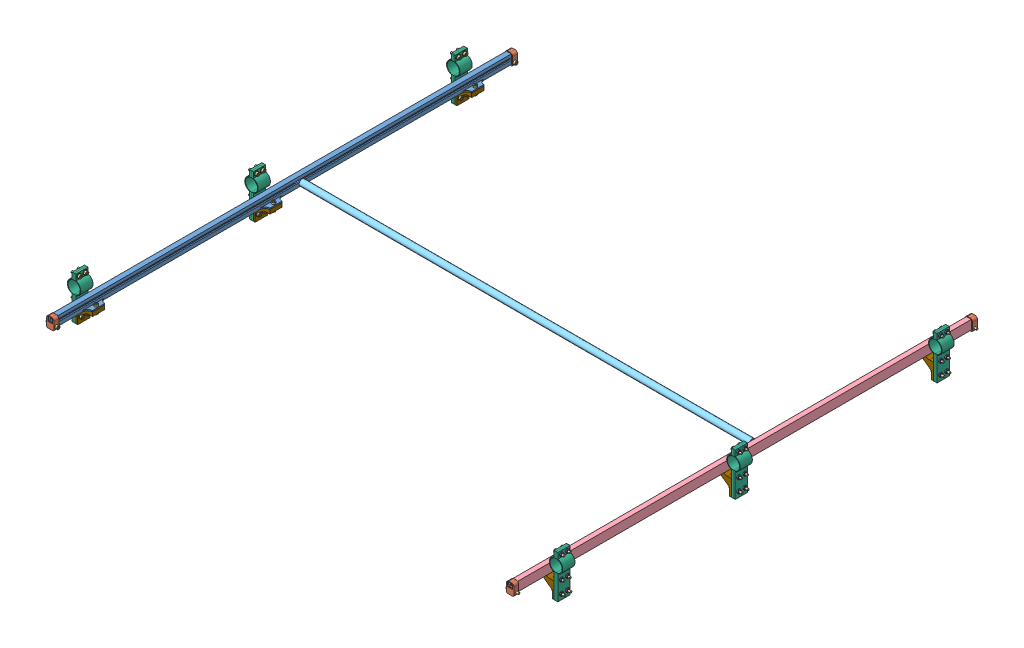
SolidWorks assembly 导轨, configuration 默认. Lengths in mm.
Overall size (810 70 758).
161 component instances, 9 part files, 34 mates.
Components (placement in the parent):
- 滑轨-1: 滑轨 [默认] at (7.799 -15.8903 -377.5) size (16 15 755)
- 滑轨孔套-1: 滑轨孔套 [默认] at (16.0944 -13.6499 379) x (-1 0 0) z (0 0 -1) size (12 18 8)
- 滑轨孔套-2: 滑轨孔套 [默认] at (8.0944 -13.6499 -379) size (12 18 8)
- hexagon socket head cap screws gb-2: hexagon socket head cap screws gb [GB_FASTENER_SCREWS_HSHCS M3X16-N] at (21.0944 -11.1499 374.5) x (-1 0 0) z (0 0.924225 0.381849) size (19 5.5 5.5)
- hexagon socket head cap screws gb-3: hexagon socket head cap screws gb [GB_FASTENER_SCREWS_HSHCS M3X16-N] at (21.0944 -11.1499 -374.5) x (-1 0 0) z (0 0.924225 0.381849) size (19 5.5 5.5)
- 滑轨-右-1: 滑轨-右 [默认] at (759.799 -15.8903 -377.5) size (16 15 755)
- hexagon socket head cap screws gb-4: hexagon socket head cap screws gb [GB_FASTENER_SCREWS_HSHCS M3X16-N] at (755.0944 -11.1499 -374.5) x (1 0 0) z (0 -0.924225 -0.381849) size (19 5.5 5.5)
- hexagon socket head cap screws gb-5: hexagon socket head cap screws gb [GB_FASTENER_SCREWS_HSHCS M3X16-N] at (755.0944 -11.1499 374.5) x (1 0 0) z (0 -0.924225 -0.381849) size (19 5.5 5.5)
- 滑轨孔套-3: 滑轨孔套 [默认] at (768.0944 -13.6499 379) x (-1 0 0) z (0 0 -1) size (12 18 8)
- 滑轨孔套-4: 滑轨孔套 [默认] at (760.0944 -13.6499 -379) size (12 18 8)
- 牵引杆-1: 牵引杆 [默认] at (8.0944 1.3501 -22.4841) x (1 0 0) z (0 0 -1) size (756 10.5 10)
- 导轨夹具-1: 导轨夹具 [默认] at (825.1435 -3.5468 -308) x (-1 0 0) z (0 0 -1) size (41 70 20)
  - 小管夹具-1: 小管夹具 [默认] at (-12.5658 -21.1975 0) size (22 70 20)
    - 夹具-1: 夹具 [默认] at (55.615 31.0944 -10) size (11 70 20)
    - 夹具-2: 夹具 [默认] at (55.615 31.0944 10) x (-1 0 0) z (0 0 -1) size (11 70 20)
    - plain washers-n series-grade a gb-2: plain washers-n series-grade a gb [GB_FASTENER_WASHER_PWNA 3] at (59.115 46.3859 5) x (0 0 -1) z (1 0 0) size (7 7 0.5)
    - plain washers-n series-grade a gb-3: plain washers-n series-grade a gb [GB_FASTENER_WASHER_PWNA 3] at (59.115 46.3859 -5) x (0 0 -1) z (1 0 0) size (7 7 0.5)
    - plain washers-n series-grade a gb-4: plain washers-n series-grade a gb [GB_FASTENER_WASHER_PWNA 3] at (59.115 10.8029 -5) x (0 0 -1) z (1 0 0) size (7 7 0.5)
    - plain washers-n series-grade a gb-5: plain washers-n series-grade a gb [GB_FASTENER_WASHER_PWNA 3] at (59.115 10.8029 5) x (0 0 -1) z (1 0 0) size (7 7 0.5)
    - hexagon socket head cap screws gb-2: hexagon socket head cap screws gb [GB_FASTENER_SCREWS_HSHCS M3X12-N] at (62.115 10.8029 -5) x (-1 0 0) z (0 0.924225 0.381849) size (15 5.5 5.5)
    - hexagon socket head cap screws gb-3: hexagon socket head cap screws gb [GB_FASTENER_SCREWS_HSHCS M3X12-N] at (62.115 10.8029 5) x (-1 0 0) z (0 0.924225 0.381849) size (15 5.5 5.5)
    - hexagon socket head cap screws gb-4: hexagon socket head cap screws gb [GB_FASTENER_SCREWS_HSHCS M3X12-N] at (62.115 46.3859 -5) x (-1 0 0) z (0 0.924225 0.381849) size (15 5.5 5.5)
    - hexagon socket head cap screws gb-5: hexagon socket head cap screws gb [GB_FASTENER_SCREWS_HSHCS M3X12-N] at (62.115 46.3859 5) x (-1 0 0) z (0 0.924225 0.381849) size (15 5.5 5.5)
    - hex nuts, style 1-grades ab gb-2: hex nuts, style 1-grades ab gb [GB_FASTENER_NUT_SNAB1 M3-N] at (50.215 10.8029 -5) x (0 0 1) z (-1 0 0) size (6.35 5.5 2.4)
    - hex nuts, style 1-grades ab gb-3: hex nuts, style 1-grades ab gb [GB_FASTENER_NUT_SNAB1 M3-N] at (50.215 10.8029 5) x (0 0 1) z (-1 0 0) size (6.35 5.5 2.4)
    - hex nuts, style 1-grades ab gb-4: hex nuts, style 1-grades ab gb [GB_FASTENER_NUT_SNAB1 M3-N] at (50.215 46.3859 -5) x (0 0 1) z (-1 0 0) size (6.35 5.5 2.4)
    - hex nuts, style 1-grades ab gb-5: hex nuts, style 1-grades ab gb [GB_FASTENER_NUT_SNAB1 M3-N] at (50.215 46.3859 5) x (0 0 1) z (-1 0 0) size (6.35 5.5 2.4)
  - 滑轨支架-1: 滑轨支架 [默认] at (49.0492 14.8969 -10) x (0 0 1) z (-1 0 0) size (20 30 27)
  - plain washers-n series-grade a gb-2: plain washers-n series-grade a gb [GB_FASTENER_WASHER_PWNA 3] at (49.5492 -30.3946 5) x (0 0 -1) z (1 0 0) size (7 7 0.5)
  - plain washers-n series-grade a gb-3: plain washers-n series-grade a gb [GB_FASTENER_WASHER_PWNA 3] at (49.5492 -30.3946 -5) x (0 0 -1) z (1 0 0) size (7 7 0.5)
  - hexagon socket head cap screws gb-2: hexagon socket head cap screws gb [GB_FASTENER_SCREWS_HSHCS M3X16-N] at (52.5492 -30.3946 5) x (-1 0 0) z (0 0.924225 0.381849) size (19 5.5 5.5)
  - hexagon socket head cap screws gb-3: hexagon socket head cap screws gb [GB_FASTENER_SCREWS_HSHCS M3X16-N] at (52.5492 -30.3946 -5) x (-1 0 0) z (0 0.924225 0.381849) size (19 5.5 5.5)
  - hex nuts, style 1-grades ab gb-2: hex nuts, style 1-grades ab gb [GB_FASTENER_NUT_SNAB1 M3-N] at (37.6492 -30.3946 5) x (0 0 1) z (-1 0 0) size (6.35 5.5 2.4)
  - hex nuts, style 1-grades ab gb-3: hex nuts, style 1-grades ab gb [GB_FASTENER_NUT_SNAB1 M3-N] at (37.6492 -30.3946 -5) x (0 0 1) z (-1 0 0) size (6.35 5.5 2.4)
- 导轨夹具-2: 导轨夹具 [默认] at (825.1435 -3.5468 22) x (-1 0 0) z (0 0 -1) size (41 70 20)
  - 小管夹具-1: 小管夹具 [默认] at (-12.5658 -21.1975 0) size (22 70 20)
    - 夹具-1: 夹具 [默认] at (55.615 31.0944 -10) size (11 70 20)
    - 夹具-2: 夹具 [默认] at (55.615 31.0944 10) x (-1 0 0) z (0 0 -1) size (11 70 20)
    - plain washers-n series-grade a gb-2: plain washers-n series-grade a gb [GB_FASTENER_WASHER_PWNA 3] at (59.115 46.3859 5) x (0 0 -1) z (1 0 0) size (7 7 0.5)
    - plain washers-n series-grade a gb-3: plain washers-n series-grade a gb [GB_FASTENER_WASHER_PWNA 3] at (59.115 46.3859 -5) x (0 0 -1) z (1 0 0) size (7 7 0.5)
    - plain washers-n series-grade a gb-4: plain washers-n series-grade a gb [GB_FASTENER_WASHER_PWNA 3] at (59.115 10.8029 -5) x (0 0 -1) z (1 0 0) size (7 7 0.5)
    - plain washers-n series-grade a gb-5: plain washers-n series-grade a gb [GB_FASTENER_WASHER_PWNA 3] at (59.115 10.8029 5) x (0 0 -1) z (1 0 0) size (7 7 0.5)
    - hexagon socket head cap screws gb-2: hexagon socket head cap screws gb [GB_FASTENER_SCREWS_HSHCS M3X12-N] at (62.115 10.8029 -5) x (-1 0 0) z (0 0.924225 0.381849) size (15 5.5 5.5)
    - hexagon socket head cap screws gb-3: hexagon socket head cap screws gb [GB_FASTENER_SCREWS_HSHCS M3X12-N] at (62.115 10.8029 5) x (-1 0 0) z (0 0.924225 0.381849) size (15 5.5 5.5)
    - hexagon socket head cap screws gb-4: hexagon socket head cap screws gb [GB_FASTENER_SCREWS_HSHCS M3X12-N] at (62.115 46.3859 -5) x (-1 0 0) z (0 0.924225 0.381849) size (15 5.5 5.5)
    - hexagon socket head cap screws gb-5: hexagon socket head cap screws gb [GB_FASTENER_SCREWS_HSHCS M3X12-N] at (62.115 46.3859 5) x (-1 0 0) z (0 0.924225 0.381849) size (15 5.5 5.5)
    - hex nuts, style 1-grades ab gb-2: hex nuts, style 1-grades ab gb [GB_FASTENER_NUT_SNAB1 M3-N] at (50.215 10.8029 -5) x (0 0 1) z (-1 0 0) size (6.35 5.5 2.4)
    - hex nuts, style 1-grades ab gb-3: hex nuts, style 1-grades ab gb [GB_FASTENER_NUT_SNAB1 M3-N] at (50.215 10.8029 5) x (0 0 1) z (-1 0 0) size (6.35 5.5 2.4)
    - hex nuts, style 1-grades ab gb-4: hex nuts, style 1-grades ab gb [GB_FASTENER_NUT_SNAB1 M3-N] at (50.215 46.3859 -5) x (0 0 1) z (-1 0 0) size (6.35 5.5 2.4)
    - hex nuts, style 1-grades ab gb-5: hex nuts, style 1-grades ab gb [GB_FASTENER_NUT_SNAB1 M3-N] at (50.215 46.3859 5) x (0 0 1) z (-1 0 0) size (6.35 5.5 2.4)
  - 滑轨支架-1: 滑轨支架 [默认] at (49.0492 14.8969 -10) x (0 0 1) z (-1 0 0) size (20 30 27)
  - plain washers-n series-grade a gb-2: plain washers-n series-grade a gb [GB_FASTENER_WASHER_PWNA 3] at (49.5492 -30.3946 5) x (0 0 -1) z (1 0 0) size (7 7 0.5)
  - plain washers-n series-grade a gb-3: plain washers-n series-grade a gb [GB_FASTENER_WASHER_PWNA 3] at (49.5492 -30.3946 -5) x (0 0 -1) z (1 0 0) size (7 7 0.5)
  - hexagon socket head cap screws gb-2: hexagon socket head cap screws gb [GB_FASTENER_SCREWS_HSHCS M3X16-N] at (52.5492 -30.3946 5) x (-1 0 0) z (0 0.924225 0.381849) size (19 5.5 5.5)
  - hexagon socket head cap screws gb-3: hexagon socket head cap screws gb [GB_FASTENER_SCREWS_HSHCS M3X16-N] at (52.5492 -30.3946 -5) x (-1 0 0) z (0 0.924225 0.381849) size (19 5.5 5.5)
  - hex nuts, style 1-grades ab gb-2: hex nuts, style 1-grades ab gb [GB_FASTENER_NUT_SNAB1 M3-N] at (37.6492 -30.3946 5) x (0 0 1) z (-1 0 0) size (6.35 5.5 2.4)
  - hex nuts, style 1-grades ab gb-3: hex nuts, style 1-grades ab gb [GB_FASTENER_NUT_SNAB1 M3-N] at (37.6492 -30.3946 -5) x (0 0 1) z (-1 0 0) size (6.35 5.5 2.4)
- 导轨夹具-3: 导轨夹具 [默认] at (825.1435 -3.5468 312) x (-1 0 0) z (0 0 -1) size (41 70 20)
  - 小管夹具-1: 小管夹具 [默认] at (-12.5658 -21.1975 0) size (22 70 20)
    - 夹具-1: 夹具 [默认] at (55.615 31.0944 -10) size (11 70 20)
    - 夹具-2: 夹具 [默认] at (55.615 31.0944 10) x (-1 0 0) z (0 0 -1) size (11 70 20)
    - plain washers-n series-grade a gb-2: plain washers-n series-grade a gb [GB_FASTENER_WASHER_PWNA 3] at (59.115 46.3859 5) x (0 0 -1) z (1 0 0) size (7 7 0.5)
    - plain washers-n series-grade a gb-3: plain washers-n series-grade a gb [GB_FASTENER_WASHER_PWNA 3] at (59.115 46.3859 -5) x (0 0 -1) z (1 0 0) size (7 7 0.5)
    - plain washers-n series-grade a gb-4: plain washers-n series-grade a gb [GB_FASTENER_WASHER_PWNA 3] at (59.115 10.8029 -5) x (0 0 -1) z (1 0 0) size (7 7 0.5)
    - plain washers-n series-grade a gb-5: plain washers-n series-grade a gb [GB_FASTENER_WASHER_PWNA 3] at (59.115 10.8029 5) x (0 0 -1) z (1 0 0) size (7 7 0.5)
    - hexagon socket head cap screws gb-2: hexagon socket head cap screws gb [GB_FASTENER_SCREWS_HSHCS M3X12-N] at (62.115 10.8029 -5) x (-1 0 0) z (0 0.924225 0.381849) size (15 5.5 5.5)
    - hexagon socket head cap screws gb-3: hexagon socket head cap screws gb [GB_FASTENER_SCREWS_HSHCS M3X12-N] at (62.115 10.8029 5) x (-1 0 0) z (0 0.924225 0.381849) size (15 5.5 5.5)
    - hexagon socket head cap screws gb-4: hexagon socket head cap screws gb [GB_FASTENER_SCREWS_HSHCS M3X12-N] at (62.115 46.3859 -5) x (-1 0 0) z (0 0.924225 0.381849) size (15 5.5 5.5)
    - hexagon socket head cap screws gb-5: hexagon socket head cap screws gb [GB_FASTENER_SCREWS_HSHCS M3X12-N] at (62.115 46.3859 5) x (-1 0 0) z (0 0.924225 0.381849) size (15 5.5 5.5)
    - hex nuts, style 1-grades ab gb-2: hex nuts, style 1-grades ab gb [GB_FASTENER_NUT_SNAB1 M3-N] at (50.215 10.8029 -5) x (0 0 1) z (-1 0 0) size (6.35 5.5 2.4)
    - hex nuts, style 1-grades ab gb-3: hex nuts, style 1-grades ab gb [GB_FASTENER_NUT_SNAB1 M3-N] at (50.215 10.8029 5) x (0 0 1) z (-1 0 0) size (6.35 5.5 2.4)
    - hex nuts, style 1-grades ab gb-4: hex nuts, style 1-grades ab gb [GB_FASTENER_NUT_SNAB1 M3-N] at (50.215 46.3859 -5) x (0 0 1) z (-1 0 0) size (6.35 5.5 2.4)
    - hex nuts, style 1-grades ab gb-5: hex nuts, style 1-grades ab gb [GB_FASTENER_NUT_SNAB1 M3-N] at (50.215 46.3859 5) x (0 0 1) z (-1 0 0) size (6.35 5.5 2.4)
  - 滑轨支架-1: 滑轨支架 [默认] at (49.0492 14.8969 -10) x (0 0 1) z (-1 0 0) size (20 30 27)
  - plain washers-n series-grade a gb-2: plain washers-n series-grade a gb [GB_FASTENER_WASHER_PWNA 3] at (49.5492 -30.3946 5) x (0 0 -1) z (1 0 0) size (7 7 0.5)
  - plain washers-n series-grade a gb-3: plain washers-n series-grade a gb [GB_FASTENER_WASHER_PWNA 3] at (49.5492 -30.3946 -5) x (0 0 -1) z (1 0 0) size (7 7 0.5)
  - hexagon socket head cap screws gb-2: hexagon socket head cap screws gb [GB_FASTENER_SCREWS_HSHCS M3X16-N] at (52.5492 -30.3946 5) x (-1 0 0) z (0 0.924225 0.381849) size (19 5.5 5.5)
  - hexagon socket head cap screws gb-3: hexagon socket head cap screws gb [GB_FASTENER_SCREWS_HSHCS M3X16-N] at (52.5492 -30.3946 -5) x (-1 0 0) z (0 0.924225 0.381849) size (19 5.5 5.5)
  - hex nuts, style 1-grades ab gb-2: hex nuts, style 1-grades ab gb [GB_FASTENER_NUT_SNAB1 M3-N] at (37.6492 -30.3946 5) x (0 0 1) z (-1 0 0) size (6.35 5.5 2.4)
  - hex nuts, style 1-grades ab gb-3: hex nuts, style 1-grades ab gb [GB_FASTENER_NUT_SNAB1 M3-N] at (37.6492 -30.3946 -5) x (0 0 1) z (-1 0 0) size (6.35 5.5 2.4)
- hexagon socket head cap screws gb-9: hexagon socket head cap screws gb [GB_FASTENER_SCREWS_HSHCS M3X12-N] at (756.0944 -8.6499 312) x (0 -1 0) z (0 0 1) size (15 5.5 5.5)
- hexagon socket head cap screws gb-10: hexagon socket head cap screws gb [GB_FASTENER_SCREWS_HSHCS M3X12-N] at (756.0944 -8.6499 22) x (0 -1 0) z (0 0 1) size (15 5.5 5.5)
- hexagon socket head cap screws gb-11: hexagon socket head cap screws gb [GB_FASTENER_SCREWS_HSHCS M3X12-N] at (756.0944 -8.6499 -308) x (0 -1 0) z (0 0 1) size (15 5.5 5.5)
- hex nuts, style 1-grades ab gb-2: hex nuts, style 1-grades ab gb [GB_FASTENER_NUT_SNAB1 M3-N] at (756.0944 -22.5499 22) x (1 0 0) z (0 -1 0) size (6.35 5.5 2.4)
- hex nuts, style 1-grades ab gb-4: hex nuts, style 1-grades ab gb [GB_FASTENER_NUT_SNAB1 M3-N] at (756.0944 -22.5499 -308) x (1 0 0) z (0 -1 0) size (6.35 5.5 2.4)
- hex nuts, style 1-grades ab gb-5: hex nuts, style 1-grades ab gb [GB_FASTENER_NUT_SNAB1 M3-N] at (756.0944 -22.5499 312) x (1 0 0) z (0 -1 0) size (6.35 5.5 2.4)
- hex nuts, style 1-grades ab gb-9: hex nuts, style 1-grades ab gb [GB_FASTENER_NUT_SNAB1 M3-N] at (20.0944 -20.1499 312) x (-1 0 0) z (0 1 0) size (6.35 5.5 2.4)
- hex nuts, style 1-grades ab gb-10: hex nuts, style 1-grades ab gb [GB_FASTENER_NUT_SNAB1 M3-N] at (20.0944 -20.1499 -308) x (-1 0 0) z (0 1 0) size (6.35 5.5 2.4)
- hex nuts, style 1-grades ab gb-11: hex nuts, style 1-grades ab gb [GB_FASTENER_NUT_SNAB1 M3-N] at (20.0944 -20.1499 22) x (-1 0 0) z (0 1 0) size (6.35 5.5 2.4)
- hexagon socket head cap screws gb-15: hexagon socket head cap screws gb [GB_FASTENER_SCREWS_HSHCS M3X12-N] at (20.0944 -8.6499 -308) x (0 -1 0) z (0 0 -1) size (15 5.5 5.5)
- hexagon socket head cap screws gb-16: hexagon socket head cap screws gb [GB_FASTENER_SCREWS_HSHCS M3X12-N] at (20.0944 -8.6499 22) x (0 -1 0) z (0 0 -1) size (15 5.5 5.5)
- hexagon socket head cap screws gb-17: hexagon socket head cap screws gb [GB_FASTENER_SCREWS_HSHCS M3X12-N] at (20.0944 -8.6499 312) x (0 -1 0) z (0 0 -1) size (15 5.5 5.5)
- 导轨夹具-5: 导轨夹具 [默认] at (-48.9548 -3.5468 312) size (41 70 20)
  - 小管夹具-1: 小管夹具 [默认] at (-12.5658 -21.1975 0) size (22 70 20)
    - 夹具-1: 夹具 [默认] at (55.615 31.0944 -10) size (11 70 20)
    - 夹具-2: 夹具 [默认] at (55.615 31.0944 10) x (-1 0 0) z (0 0 -1) size (11 70 20)
    - plain washers-n series-grade a gb-2: plain washers-n series-grade a gb [GB_FASTENER_WASHER_PWNA 3] at (59.115 46.3859 5) x (0 0 -1) z (1 0 0) size (7 7 0.5)
    - plain washers-n series-grade a gb-3: plain washers-n series-grade a gb [GB_FASTENER_WASHER_PWNA 3] at (59.115 46.3859 -5) x (0 0 -1) z (1 0 0) size (7 7 0.5)
    - plain washers-n series-grade a gb-4: plain washers-n series-grade a gb [GB_FASTENER_WASHER_PWNA 3] at (59.115 10.8029 -5) x (0 0 -1) z (1 0 0) size (7 7 0.5)
    - plain washers-n series-grade a gb-5: plain washers-n series-grade a gb [GB_FASTENER_WASHER_PWNA 3] at (59.115 10.8029 5) x (0 0 -1) z (1 0 0) size (7 7 0.5)
    - hexagon socket head cap screws gb-2: hexagon socket head cap screws gb [GB_FASTENER_SCREWS_HSHCS M3X12-N] at (62.115 10.8029 -5) x (-1 0 0) z (0 0.924225 0.381849) size (15 5.5 5.5)
    - hexagon socket head cap screws gb-3: hexagon socket head cap screws gb [GB_FASTENER_SCREWS_HSHCS M3X12-N] at (62.115 10.8029 5) x (-1 0 0) z (0 0.924225 0.381849) size (15 5.5 5.5)
    - hexagon socket head cap screws gb-4: hexagon socket head cap screws gb [GB_FASTENER_SCREWS_HSHCS M3X12-N] at (62.115 46.3859 -5) x (-1 0 0) z (0 0.924225 0.381849) size (15 5.5 5.5)
    - hexagon socket head cap screws gb-5: hexagon socket head cap screws gb [GB_FASTENER_SCREWS_HSHCS M3X12-N] at (62.115 46.3859 5) x (-1 0 0) z (0 0.924225 0.381849) size (15 5.5 5.5)
    - hex nuts, style 1-grades ab gb-2: hex nuts, style 1-grades ab gb [GB_FASTENER_NUT_SNAB1 M3-N] at (50.215 10.8029 -5) x (0 0 1) z (-1 0 0) size (6.35 5.5 2.4)
    - hex nuts, style 1-grades ab gb-3: hex nuts, style 1-grades ab gb [GB_FASTENER_NUT_SNAB1 M3-N] at (50.215 10.8029 5) x (0 0 1) z (-1 0 0) size (6.35 5.5 2.4)
    - hex nuts, style 1-grades ab gb-4: hex nuts, style 1-grades ab gb [GB_FASTENER_NUT_SNAB1 M3-N] at (50.215 46.3859 -5) x (0 0 1) z (-1 0 0) size (6.35 5.5 2.4)
    - hex nuts, style 1-grades ab gb-5: hex nuts, style 1-grades ab gb [GB_FASTENER_NUT_SNAB1 M3-N] at (50.215 46.3859 5) x (0 0 1) z (-1 0 0) size (6.35 5.5 2.4)
  - 滑轨支架-1: 滑轨支架 [默认] at (49.0492 14.8969 -10) x (0 0 1) z (-1 0 0) size (20 30 27)
  - plain washers-n series-grade a gb-2: plain washers-n series-grade a gb [GB_FASTENER_WASHER_PWNA 3] at (49.5492 -30.3946 5) x (0 0 -1) z (1 0 0) size (7 7 0.5)
  - plain washers-n series-grade a gb-3: plain washers-n series-grade a gb [GB_FASTENER_WASHER_PWNA 3] at (49.5492 -30.3946 -5) x (0 0 -1) z (1 0 0) size (7 7 0.5)
  - hexagon socket head cap screws gb-2: hexagon socket head cap screws gb [GB_FASTENER_SCREWS_HSHCS M3X16-N] at (52.5492 -30.3946 5) x (-1 0 0) z (0 0.924225 0.381849) size (19 5.5 5.5)
  - hexagon socket head cap screws gb-3: hexagon socket head cap screws gb [GB_FASTENER_SCREWS_HSHCS M3X16-N] at (52.5492 -30.3946 -5) x (-1 0 0) z (0 0.924225 0.381849) size (19 5.5 5.5)
  - hex nuts, style 1-grades ab gb-2: hex nuts, style 1-grades ab gb [GB_FASTENER_NUT_SNAB1 M3-N] at (37.6492 -30.3946 5) x (0 0 1) z (-1 0 0) size (6.35 5.5 2.4)
  - hex nuts, style 1-grades ab gb-3: hex nuts, style 1-grades ab gb [GB_FASTENER_NUT_SNAB1 M3-N] at (37.6492 -30.3946 -5) x (0 0 1) z (-1 0 0) size (6.35 5.5 2.4)
- 导轨夹具-6: 导轨夹具 [默认] at (-48.9548 -3.5468 -308) size (41 70 20)
  - 小管夹具-1: 小管夹具 [默认] at (-12.5658 -21.1975 0) size (22 70 20)
    - 夹具-1: 夹具 [默认] at (55.615 31.0944 -10) size (11 70 20)
    - 夹具-2: 夹具 [默认] at (55.615 31.0944 10) x (-1 0 0) z (0 0 -1) size (11 70 20)
    - plain washers-n series-grade a gb-2: plain washers-n series-grade a gb [GB_FASTENER_WASHER_PWNA 3] at (59.115 46.3859 5) x (0 0 -1) z (1 0 0) size (7 7 0.5)
    - plain washers-n series-grade a gb-3: plain washers-n series-grade a gb [GB_FASTENER_WASHER_PWNA 3] at (59.115 46.3859 -5) x (0 0 -1) z (1 0 0) size (7 7 0.5)
    - plain washers-n series-grade a gb-4: plain washers-n series-grade a gb [GB_FASTENER_WASHER_PWNA 3] at (59.115 10.8029 -5) x (0 0 -1) z (1 0 0) size (7 7 0.5)
    - plain washers-n series-grade a gb-5: plain washers-n series-grade a gb [GB_FASTENER_WASHER_PWNA 3] at (59.115 10.8029 5) x (0 0 -1) z (1 0 0) size (7 7 0.5)
    - hexagon socket head cap screws gb-2: hexagon socket head cap screws gb [GB_FASTENER_SCREWS_HSHCS M3X12-N] at (62.115 10.8029 -5) x (-1 0 0) z (0 0.924225 0.381849) size (15 5.5 5.5)
    - hexagon socket head cap screws gb-3: hexagon socket head cap screws gb [GB_FASTENER_SCREWS_HSHCS M3X12-N] at (62.115 10.8029 5) x (-1 0 0) z (0 0.924225 0.381849) size (15 5.5 5.5)
    - hexagon socket head cap screws gb-4: hexagon socket head cap screws gb [GB_FASTENER_SCREWS_HSHCS M3X12-N] at (62.115 46.3859 -5) x (-1 0 0) z (0 0.924225 0.381849) size (15 5.5 5.5)
    - hexagon socket head cap screws gb-5: hexagon socket head cap screws gb [GB_FASTENER_SCREWS_HSHCS M3X12-N] at (62.115 46.3859 5) x (-1 0 0) z (0 0.924225 0.381849) size (15 5.5 5.5)
    - hex nuts, style 1-grades ab gb-2: hex nuts, style 1-grades ab gb [GB_FASTENER_NUT_SNAB1 M3-N] at (50.215 10.8029 -5) x (0 0 1) z (-1 0 0) size (6.35 5.5 2.4)
    - hex nuts, style 1-grades ab gb-3: hex nuts, style 1-grades ab gb [GB_FASTENER_NUT_SNAB1 M3-N] at (50.215 10.8029 5) x (0 0 1) z (-1 0 0) size (6.35 5.5 2.4)
    - hex nuts, style 1-grades ab gb-4: hex nuts, style 1-grades ab gb [GB_FASTENER_NUT_SNAB1 M3-N] at (50.215 46.3859 -5) x (0 0 1) z (-1 0 0) size (6.35 5.5 2.4)
    - hex nuts, style 1-grades ab gb-5: hex nuts, style 1-grades ab gb [GB_FASTENER_NUT_SNAB1 M3-N] at (50.215 46.3859 5) x (0 0 1) z (-1 0 0) size (6.35 5.5 2.4)
  - 滑轨支架-1: 滑轨支架 [默认] at (49.0492 14.8969 -10) x (0 0 1) z (-1 0 0) size (20 30 27)
  - plain washers-n series-grade a gb-2: plain washers-n series-grade a gb [GB_FASTENER_WASHER_PWNA 3] at (49.5492 -30.3946 5) x (0 0 -1) z (1 0 0) size (7 7 0.5)
  - plain washers-n series-grade a gb-3: plain washers-n series-grade a gb [GB_FASTENER_WASHER_PWNA 3] at (49.5492 -30.3946 -5) x (0 0 -1) z (1 0 0) size (7 7 0.5)
  - hexagon socket head cap screws gb-2: hexagon socket head cap screws gb [GB_FASTENER_SCREWS_HSHCS M3X16-N] at (52.5492 -30.3946 5) x (-1 0 0) z (0 0.924225 0.381849) size (19 5.5 5.5)
  - hexagon socket head cap screws gb-3: hexagon socket head cap screws gb [GB_FASTENER_SCREWS_HSHCS M3X16-N] at (52.5492 -30.3946 -5) x (-1 0 0) z (0 0.924225 0.381849) size (19 5.5 5.5)
  - hex nuts, style 1-grades ab gb-2: hex nuts, style 1-grades ab gb [GB_FASTENER_NUT_SNAB1 M3-N] at (37.6492 -30.3946 5) x (0 0 1) z (-1 0 0) size (6.35 5.5 2.4)
  - hex nuts, style 1-grades ab gb-3: hex nuts, style 1-grades ab gb [GB_FASTENER_NUT_SNAB1 M3-N] at (37.6492 -30.3946 -5) x (0 0 1) z (-1 0 0) size (6.35 5.5 2.4)
- 导轨夹具-7: 导轨夹具 [默认] at (-48.9548 -3.5468 22) size (41 70 20)
  - 小管夹具-1: 小管夹具 [默认] at (-12.5658 -21.1975 0) size (22 70 20)
    - 夹具-1: 夹具 [默认] at (55.615 31.0944 -10) size (11 70 20)
    - 夹具-2: 夹具 [默认] at (55.615 31.0944 10) x (-1 0 0) z (0 0 -1) size (11 70 20)
    - plain washers-n series-grade a gb-2: plain washers-n series-grade a gb [GB_FASTENER_WASHER_PWNA 3] at (59.115 46.3859 5) x (0 0 -1) z (1 0 0) size (7 7 0.5)
    - plain washers-n series-grade a gb-3: plain washers-n series-grade a gb [GB_FASTENER_WASHER_PWNA 3] at (59.115 46.3859 -5) x (0 0 -1) z (1 0 0) size (7 7 0.5)
    - plain washers-n series-grade a gb-4: plain washers-n series-grade a gb [GB_FASTENER_WASHER_PWNA 3] at (59.115 10.8029 -5) x (0 0 -1) z (1 0 0) size (7 7 0.5)
    - plain washers-n series-grade a gb-5: plain washers-n series-grade a gb [GB_FASTENER_WASHER_PWNA 3] at (59.115 10.8029 5) x (0 0 -1) z (1 0 0) size (7 7 0.5)
    - hexagon socket head cap screws gb-2: hexagon socket head cap screws gb [GB_FASTENER_SCREWS_HSHCS M3X12-N] at (62.115 10.8029 -5) x (-1 0 0) z (0 0.924225 0.381849) size (15 5.5 5.5)
    - hexagon socket head cap screws gb-3: hexagon socket head cap screws gb [GB_FASTENER_SCREWS_HSHCS M3X12-N] at (62.115 10.8029 5) x (-1 0 0) z (0 0.924225 0.381849) size (15 5.5 5.5)
    - hexagon socket head cap screws gb-4: hexagon socket head cap screws gb [GB_FASTENER_SCREWS_HSHCS M3X12-N] at (62.115 46.3859 -5) x (-1 0 0) z (0 0.924225 0.381849) size (15 5.5 5.5)
    - hexagon socket head cap screws gb-5: hexagon socket head cap screws gb [GB_FASTENER_SCREWS_HSHCS M3X12-N] at (62.115 46.3859 5) x (-1 0 0) z (0 0.924225 0.381849) size (15 5.5 5.5)
    - hex nuts, style 1-grades ab gb-2: hex nuts, style 1-grades ab gb [GB_FASTENER_NUT_SNAB1 M3-N] at (50.215 10.8029 -5) x (0 0 1) z (-1 0 0) size (6.35 5.5 2.4)
    - hex nuts, style 1-grades ab gb-3: hex nuts, style 1-grades ab gb [GB_FASTENER_NUT_SNAB1 M3-N] at (50.215 10.8029 5) x (0 0 1) z (-1 0 0) size (6.35 5.5 2.4)
    - hex nuts, style 1-grades ab gb-4: hex nuts, style 1-grades ab gb [GB_FASTENER_NUT_SNAB1 M3-N] at (50.215 46.3859 -5) x (0 0 1) z (-1 0 0) size (6.35 5.5 2.4)
    - hex nuts, style 1-grades ab gb-5: hex nuts, style 1-grades ab gb [GB_FASTENER_NUT_SNAB1 M3-N] at (50.215 46.3859 5) x (0 0 1) z (-1 0 0) size (6.35 5.5 2.4)
  - 滑轨支架-1: 滑轨支架 [默认] at (49.0492 14.8969 -10) x (0 0 1) z (-1 0 0) size (20 30 27)
  - plain washers-n series-grade a gb-2: plain washers-n series-grade a gb [GB_FASTENER_WASHER_PWNA 3] at (49.5492 -30.3946 5) x (0 0 -1) z (1 0 0) size (7 7 0.5)
  - plain washers-n series-grade a gb-3: plain washers-n series-grade a gb [GB_FASTENER_WASHER_PWNA 3] at (49.5492 -30.3946 -5) x (0 0 -1) z (1 0 0) size (7 7 0.5)
  - hexagon socket head cap screws gb-2: hexagon socket head cap screws gb [GB_FASTENER_SCREWS_HSHCS M3X16-N] at (52.5492 -30.3946 5) x (-1 0 0) z (0 0.924225 0.381849) size (19 5.5 5.5)
  - hexagon socket head cap screws gb-3: hexagon socket head cap screws gb [GB_FASTENER_SCREWS_HSHCS M3X16-N] at (52.5492 -30.3946 -5) x (-1 0 0) z (0 0.924225 0.381849) size (19 5.5 5.5)
  - hex nuts, style 1-grades ab gb-2: hex nuts, style 1-grades ab gb [GB_FASTENER_NUT_SNAB1 M3-N] at (37.6492 -30.3946 5) x (0 0 1) z (-1 0 0) size (6.35 5.5 2.4)
  - hex nuts, style 1-grades ab gb-3: hex nuts, style 1-grades ab gb [GB_FASTENER_NUT_SNAB1 M3-N] at (37.6492 -30.3946 -5) x (0 0 1) z (-1 0 0) size (6.35 5.5 2.4)
Mates (geometry in assembly coordinates):
- 同心3: concentric anti-aligned: cylinder of 滑轨-1 through (16.0944 -11.1499 374.5) axis (1 0 0) radius 1.25; cylinder of 滑轨孔套-1 through (6.0944 -11.1499 374.5) axis (-1 0 0) radius 1.25
- 重合3: coincident anti-aligned: plane of 滑轨-1 through (16.0944 -13.6499 377.5) normal (1 0 0); plane of 滑轨孔套-1 through (16.0944 -13.6499 371) normal (-1 0 0)
- 平行2: parallel anti-aligned: plane of 滑轨-1 through (7.799 -15.8903 377.5) normal (0 0 1); plane of 滑轨孔套-1 through (16.0944 -13.6499 371) normal (0 0 -1)
- 同心4: concentric anti-aligned: cylinder of 滑轨孔套-1 through (6.0944 -11.1499 374.5) axis (-1 0 0) radius 1.25; cylinder of hexagon socket head cap screws gb-2 through (2.0944 -11.1499 374.5) axis (1 0 0) radius 1.5
- 重合4: coincident anti-aligned: plane of 滑轨孔套-1 through (18.0944 -13.6499 371) normal (1 0 0); plane of hexagon socket head cap screws gb-2 through (18.0944 -11.1499 374.5) normal (-1 0 0)
- 同心5: concentric aligned: cylinder of 滑轨孔套-2 through (18.0944 -11.1499 -374.5) axis (1 0 0) radius 1.25; cylinder of hexagon socket head cap screws gb-3 through (2.0944 -11.1499 -374.5) axis (1 0 0) radius 1.5
- 重合5: coincident anti-aligned: plane of 滑轨孔套-2 through (18.0944 -13.6499 -371) normal (1 0 0); plane of hexagon socket head cap screws gb-3 through (18.0944 -11.1499 -374.5) normal (-1 0 0)
- 距离1: distance = 372 mm anti-aligned: plane of assembly through (388.0944 0 0) normal (1 0 0); plane of 滑轨-右-1 through (760.0944 -1.1499 377.5) normal (-1 0 0)
- 重合7: coincident aligned: plane of 滑轨-1 through (7.799 -11.6499 -377.5) normal (0 1 0); plane of 滑轨-右-1 through (759.799 -11.6499 -377.5) normal (0 1 0)
- 重合8: coincident aligned: plane of 滑轨-1 through (7.799 -15.8903 377.5) normal (0 0 1); plane of 滑轨-右-1 through (759.799 -15.8903 377.5) normal (0 0 1)
- 重合9: coincident anti-aligned: plane of 滑轨-1 through (10.0944 -1.1499 377.5) normal (1 0 0); plane of 牵引杆-1 through (10.0944 -1.1499 -27.4841) normal (-1 0 0)
- 平行4: parallel anti-aligned: plane of 滑轨-右-1 through (766.0944 -7.6499 377.5) normal (-1 0 0); plane of 牵引杆-1 through (766.0944 -1.1499 -27.4841) normal (1 0 0)
- 重合13: coincident anti-aligned: plane of 滑轨-1 through (14.0944 -1.1499 377.5) normal (0 -1 0); plane of 牵引杆-1 through (14.0944 -1.1499 -27.4841) normal (0 1 0)
- 同心61: concentric anti-aligned: cylinder of 滑轨-右-1 through (756.0944 -11.6499 -308) axis (0 -1 0) radius 1.5; cylinder of 导轨夹具-1/滑轨支架-1 through (756.0944 -27.1499 -308) axis (0 1 0) radius 1.5
- 重合141: coincident aligned: plane of 滑轨-右-1 through (752.0944 -11.6499 -318) normal (-1 0 0); plane of 导轨夹具-1/滑轨支架-1 through (752.0944 11.3501 -298) normal (-1 0 0)
- 重合151: coincident anti-aligned: plane of 滑轨-右-1 through (760.0944 -13.6499 377.5) normal (0 -1 0); plane of 导轨夹具-1/滑轨支架-1 through (764.5944 -13.6499 -318) normal (0 1 0)
- 同心71: concentric anti-aligned: cylinder of 滑轨-右-1 through (756.0944 -11.6499 22) axis (0 -1 0) radius 1.5; cylinder of 导轨夹具-2/滑轨支架-1 through (756.0944 -27.1499 22) axis (0 1 0) radius 1.5
- 重合161: coincident aligned: plane of 滑轨-右-1 through (752.0944 -11.6499 12) normal (-1 0 0); plane of 导轨夹具-2/滑轨支架-1 through (752.0944 11.3501 32) normal (-1 0 0)
- 重合171: coincident anti-aligned: plane of 滑轨-右-1 through (760.0944 -13.6499 377.5) normal (0 -1 0); plane of 导轨夹具-2/滑轨支架-1 through (764.5944 -13.6499 12) normal (0 1 0)
- 同心81: concentric anti-aligned: cylinder of 滑轨-右-1 through (756.0944 -11.6499 312) axis (0 -1 0) radius 1.5; cylinder of 导轨夹具-3/滑轨支架-1 through (756.0944 -27.1499 312) axis (0 1 0) radius 1.5
- 重合181: coincident aligned: plane of 滑轨-右-1 through (752.0944 -11.6499 302) normal (-1 0 0); plane of 导轨夹具-3/滑轨支架-1 through (752.0944 11.3501 322) normal (-1 0 0)
- 重合191: coincident anti-aligned: plane of 滑轨-右-1 through (760.0944 -13.6499 377.5) normal (0 -1 0); plane of 导轨夹具-3/滑轨支架-1 through (764.5944 -13.6499 302) normal (0 1 0)
- 同心10: concentric anti-aligned: cylinder of 滑轨-右-1 through (756.0944 -11.6499 312) axis (0 -1 0) radius 1.5; cylinder of hexagon socket head cap screws gb-9 through (756.0944 -23.6499 312) axis (0 1 0) radius 1.5
- 重合20: coincident anti-aligned: plane of 滑轨-右-1 through (759.799 -11.6499 -377.5) normal (0 1 0); plane of hexagon socket head cap screws gb-9 through (756.0944 -11.6499 312) normal (0 -1 0)
- 同心11: concentric anti-aligned: cylinder of 滑轨-右-1 through (756.0944 -11.6499 22) axis (0 -1 0) radius 1.5; cylinder of hexagon socket head cap screws gb-10 through (756.0944 -23.6499 22) axis (0 1 0) radius 1.5
- 重合21: coincident anti-aligned: plane of 滑轨-右-1 through (759.799 -11.6499 -377.5) normal (0 1 0); plane of hexagon socket head cap screws gb-10 through (756.0944 -11.6499 22) normal (0 -1 0)
- 同心12: concentric anti-aligned: cylinder of 滑轨-右-1 through (756.0944 -11.6499 -308) axis (0 -1 0) radius 1.5; cylinder of hexagon socket head cap screws gb-11 through (756.0944 -23.6499 -308) axis (0 1 0) radius 1.5
- 重合22: coincident anti-aligned: plane of 滑轨-右-1 through (759.799 -11.6499 -377.5) normal (0 1 0); plane of hexagon socket head cap screws gb-11 through (756.0944 -11.6499 -308) normal (0 -1 0)
- 同心13: concentric anti-aligned: cylinder of hexagon socket head cap screws gb-10 through (756.0944 -23.6499 22) axis (0 1 0) radius 1.5; cone of hex nuts, style 1-grades ab gb-2 through (756.0944 -20.1499 22) axis (0 -1 0)
- 重合23: coincident anti-aligned: plane of 导轨夹具-2/滑轨支架-1 through (752.0944 -20.1499 12) normal (0 -1 0); plane of hex nuts, style 1-grades ab gb-2 through (756.0944 -20.1499 16.5) normal (0 1 0)
- 同心14: concentric anti-aligned: cylinder of hexagon socket head cap screws gb-11 through (756.0944 -23.6499 -308) axis (0 1 0) radius 1.5; cone of hex nuts, style 1-grades ab gb-4 through (756.0944 -20.1499 -308) axis (0 -1 0)
- 重合24: coincident anti-aligned: plane of 导轨夹具-1/滑轨支架-1 through (752.0944 -20.1499 -318) normal (0 -1 0); plane of hex nuts, style 1-grades ab gb-4 through (756.0944 -20.1499 -313.5) normal (0 1 0)
- 同心15: concentric anti-aligned: cylinder of hexagon socket head cap screws gb-9 through (756.0944 -23.6499 312) axis (0 1 0) radius 1.5; cone of hex nuts, style 1-grades ab gb-5 through (756.0944 -20.1499 312) axis (0 -1 0)
- 重合25: coincident anti-aligned: plane of 导轨夹具-3/滑轨支架-1 through (752.0944 -20.1499 302) normal (0 -1 0); plane of hex nuts, style 1-grades ab gb-5 through (756.0944 -20.1499 306.5) normal (0 1 0)
